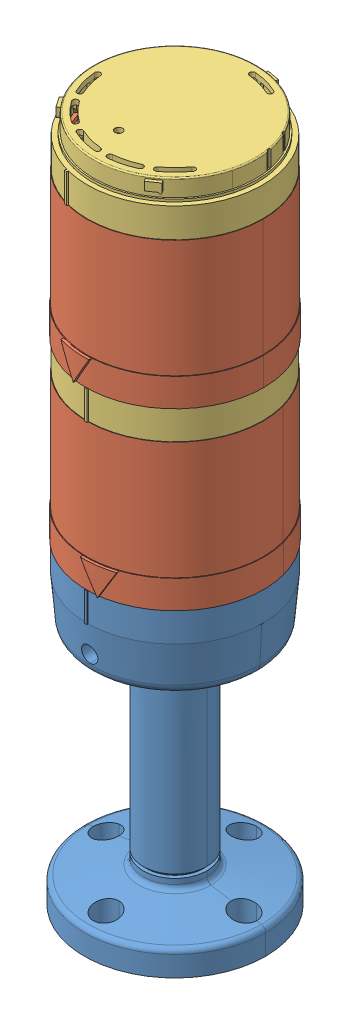
SolidWorks assembly StackLight_Assembly, configuration Default. Lengths in mm.
Overall size (103.25 272.82 103.6).
9 component instances, 3 part files, 9 mates.
Components (placement in the parent):
- 855t-bpm10-1: 855t-bpm10 [Default] at origin size (86.66 148.75 88.63)
- 855t_module-1: 855t_module [Default] at (0 98.5 0) size (84.2 76.26 84.69)
  - 855t_module(2)^855t_module-1: 855t_module(2)^855t_module [Default] at origin size (84.2 76.26 84.69) (virtual)
    - 40378-011^855t_module(2)_855t_module-1: 40378-011^855t_module(2)_855t_module [Default] at origin size (69.5 65.01 72.38) (virtual)
    - 40378-007^855t_module(2)_855t_module-1: 40378-007^855t_module(2)_855t_module [Default] at (0 57 0) x (0.965926 0 0.258819) z (-0.258819 0 0.965926) size (68.6 19.75 69.3) (virtual)
- 855t_module-2: 855t_module [Default] at (0 30 0) x (0.965926 0 -0.258819) z (0.258819 0 0.965926) size (84.2 76.26 84.69)
  - 855t_module(2)^855t_module-1: 855t_module(2)^855t_module [Default] at origin size (84.2 76.26 84.69) (virtual)
    - 40378-011^855t_module(2)_855t_module-1: 40378-011^855t_module(2)_855t_module [Default] at origin size (69.5 65.01 72.38) (virtual)
    - 40378-007^855t_module(2)_855t_module-1: 40378-007^855t_module(2)_855t_module [Default] at (0 57 0) x (0.965926 0 0.258819) z (-0.258819 0 0.965926) size (68.6 19.75 69.3) (virtual)
Mates (geometry in assembly coordinates):
- Concentric2: concentric anti-aligned: cylinder of 855t_module-1/855t_module.stp-1/40378-007.stp-1 through (0 168.05 0) axis (0 -1 0) radius 32.4; cylinder of 855t_module-2/855t_module(2)^855t_module-1/40378-011^855t_module(2)_855t_module-1 through (0 29.92 0) axis (0 1 0) radius 33.75
- Coincident2: coincident anti-aligned: plane of 855t_module-1/855t_module(2)^855t_module-1/40378-011^855t_module(2)_855t_module-1 through (0 98.5 0) normal (0 -1 0); plane of 855t_module-2/855t_module(2)^855t_module-1/40378-007^855t_module(2)_855t_module-1 through (0 98.5 0) normal (0 1 0)
- Coincident3: coincident anti-aligned: plane of 855t-bpm10-1 through (0 30 0) normal (0 1 0); plane of 855t_module-2/855t_module(2)^855t_module-1/40378-011^855t_module(2)_855t_module-1 through (0 30 0) normal (0 -1 0)
- Coincident4: coincident aligned: plane of 855t-bpm10-1 through (0 0 0) normal (0 0 1)
- Coincident5: coincident aligned: plane of 855t-bpm10-1 through (0 0 0) normal (0 1 0)
- Coincident6: coincident aligned: plane of 855t-bpm10-1 through (0 0 0) normal (1 0 0)
- Coincident7: coincident aligned: plane of 855t_module-1 through (0 98.5 0) normal (0 0 1)
- Coincident8: coincident aligned: plane of 855t_module-1 through (0 98.5 0) normal (1 0 0)
- Coincident9: coincident aligned: plane of 855t-bpm10-1 through (0.5 18.5 35) normal (1 0 0); plane of 855t_module-2/855t_module(2)^855t_module-1/40378-007^855t_module(2)_855t_module-1 through (0.5 87 35) normal (1 0 0)
